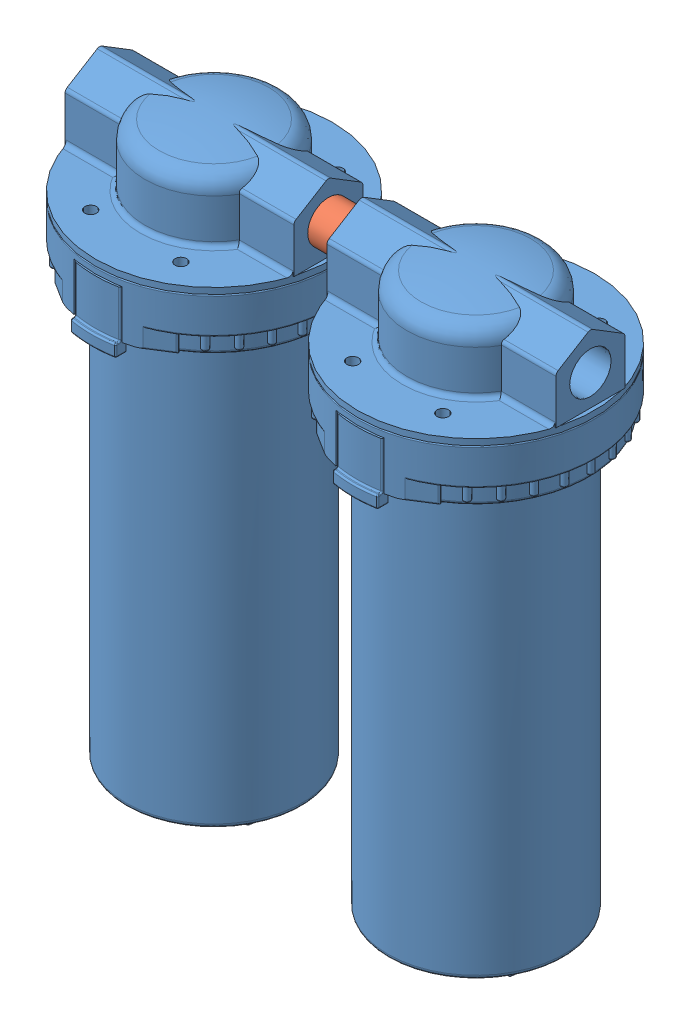
SolidWorks assembly ReadingTech_4P-060-M03-DCP, configuration Default. Lengths in mm.
Overall size (206.63 246.51 99.95).
3 component instances, 2 part files, 3 mates.
Components (placement in the parent):
- ReadingTech_3P-060-M03-P-1: ReadingTech_3P-060-M03-P [Default] at (-38.8999 -100.2244 14.1715) size (98.17 246.51 99.95)
- ReadingTech_3P-060-M03-P-2: ReadingTech_3P-060-M03-P [Default] at (69.5581 -100.2244 14.1715) size (98.17 246.51 99.95)
- ReadingTech- 60cfm_connector_.375in-1: ReadingTech- 60cfm_connector_.375in [Default] at (22.1871 115.6756 14.1715) x (0 1 0) z (0 0 1) size (17.14 13.72 17.14)
Mates (geometry in assembly coordinates):
- Coincident1: coincident anti-aligned: circle of ReadingTech_3P-060-M03-P-1; circle of ReadingTech- 60cfm_connector_.375in-1
- Coincident2: coincident aligned: circle of ReadingTech_3P-060-M03-P-2; circle of ReadingTech- 60cfm_connector_.375in-1
- Coincident3: coincident aligned: plane of ReadingTech_3P-060-M03-P-1 through (8.4711 102.9756 28.459) normal (0 0 1); plane of ReadingTech_3P-060-M03-P-2 through (116.9291 102.9756 28.459) normal (0 0 1)
